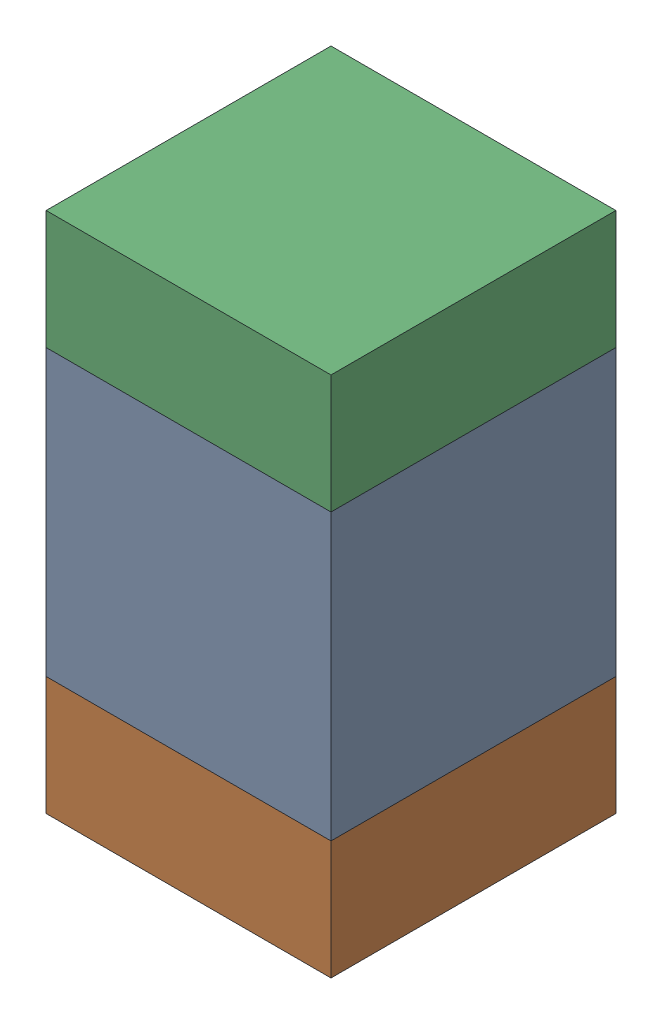
SolidWorks assembly C413PCB, configuration Default. Lengths in mm.
Overall size (0.6 1.1 0.6).
6 component instances, 2 part files, 0 mates.
Components (placement in the parent):
- 761606048-1: 761606048 [Default] at (83.39 90.8 0) size (0.6 0.6 0.6)
  - Extruded_9-1: Extruded_9 [Default] at origin size (0.6 0.6 0.6)
- 854785296-1: 854785296 [Default] at (83.39 90.375 0) size (0.6 0.25 0.6)
  - Extruded_10-1: Extruded_10 [Default] at origin size (0.6 0.25 0.6)
- 854785296-2: 854785296 [Default] at (83.39 91.225 0) size (0.6 0.25 0.6)
  - Extruded_10-1: Extruded_10 [Default] at origin size (0.6 0.25 0.6)
